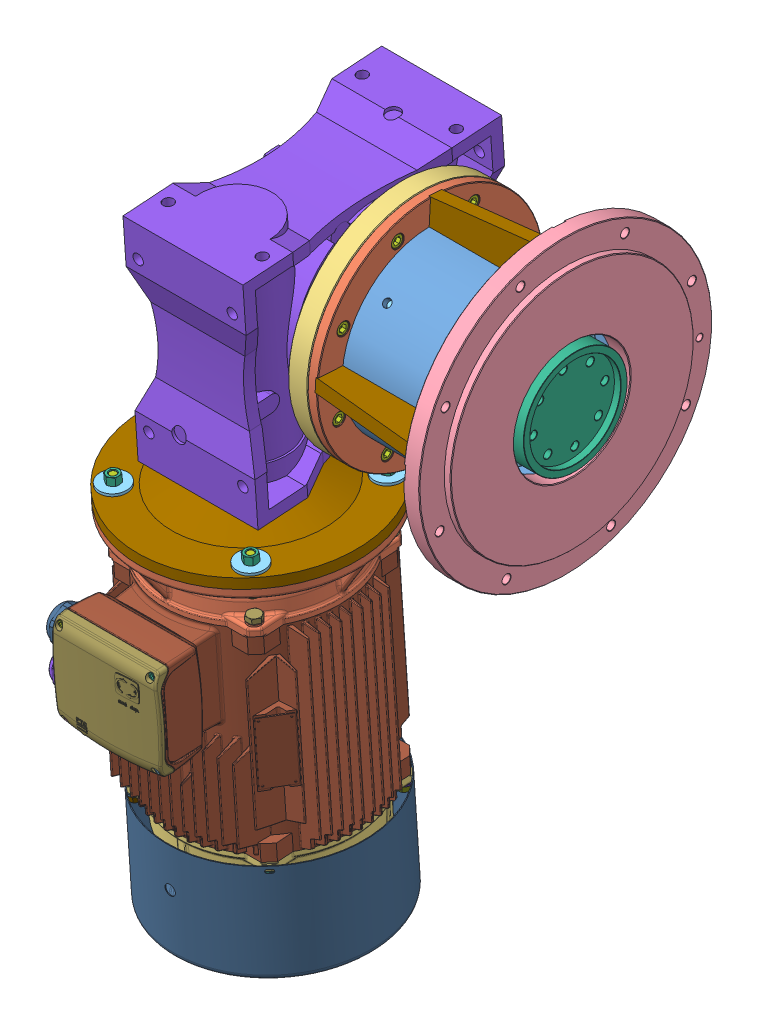
SolidWorks assembly assemblage vireur fini 15.03.2014, configuration Défaut. Lengths in mm.
Overall size (543.11 1035.69 624.79).
75 component instances, 45 part files, 72 mates.
Components (placement in the parent):
- Tube 10 pouce-1: Tube 10 pouce [Défaut] at (-85.911 6.4326 0) size (193.5 273 273)
- Bride tube-1: Bride tube [Défaut] at (-100.411 6.4326 0) x (0 0.056355 0.998411) z (0 -0.998411 0.056355) size (350 19.5 350)
- Bride motoreducteur-1: Bride motoreducteur [Défaut] at (-120.911 6.4326 0) x (0 -0.056355 -0.998411) z (0 0.998411 -0.056355) size (350 30 350)
- bride reducteur GV-1: bride reducteur GV [Défaut] at (107.589 6.4326 0) x (0 -0.998411 0.056355) z (0 -0.056355 -0.998411) size (452 35 452)
- assembla electro du 26;01-1: assembla electro du 26;01 [Défaut] at (-2.5361 8.8665 -55.0034) x (1 0 0) z (0 -0.185944 0.98256) size (265.12 217.99 217.99)
  - Embrayage electro magnetique2-1: Embrayage electro magnetique2 [Défaut] at (-536.0163 -265.8827 54.4967) size (235.12 217.99 217.99)
  - manchon2-1: manchon2 [Défaut] at (135.1251 7.836 54.4967) x (1 0 0) z (0 -0.999668 0.025764) size (110 160 160)
- socket head cap screw_iso-1: socket head cap screw_iso [ISO 4762 M12 x 25 --- 25C] at (-81.911 147.5918 50.7353) x (-1 0 0) z (0 0.471844 0.881682) size (37 18 18)
- socket head cap screw_iso-2: socket head cap screw_iso [ISO 4762 M12 x 25 --- 25C] at (-81.911 -134.7267 -50.7353) x (-1 0 0) z (0 -0.269981 0.962866) size (37 18 18)
- socket head cap screw_iso-3: socket head cap screw_iso [ISO 4762 M12 x 25 --- 25C] at (-81.911 -44.3027 141.1592) x (-1 0 0) z (0 -0.153649 0.988125) size (37 18 18)
- socket head cap screw_iso-4: socket head cap screw_iso [ISO 4762 M12 x 25 --- 25C] at (-81.911 -128.1208 66.2978) x (-1 0 0) z (0 -0.217951 0.97596) size (37 18 18)
- socket head cap screw_iso-5: socket head cap screw_iso [ISO 4762 M12 x 25 --- 25C] at (-81.911 72.7303 134.5534) x (-1 0 0) z (0 0.044455 0.999011) size (37 18 18)
- socket head cap screw_iso-6: socket head cap screw_iso [ISO 4762 M12 x 25 --- 25C] at (-81.911 -59.8652 -134.5534) x (-1 0 0) z (0 -0.742748 0.669571) size (37 18 18)
- socket head cap screw_iso-7: socket head cap screw_iso [ISO 4762 M12 x 25 --- 25C] at (-81.911 57.1678 -141.1592) x (-1 0 0) z (0 0.620775 0.783989) size (37 18 18)
- socket head cap screw_iso-8: socket head cap screw_iso [ISO 4762 M12 x 25 --- 25C] at (-81.911 140.9859 -66.2978) x (-1 0 0) z (0 -0.169231 0.985576) size (37 18 18)
- reducteur box 150-1: reducteur box 150 [Défaut] at (-221.911 6.4326 0) x (0 -0.99765 -0.068517) z (-1 0 0) size (382.6 495 350)
  - box150-1: box150 [Défaut] x (-1 0 0) z (0 0 -1) size (342.6 400 200)
  - Box150 Input Flanges_160B5-1: Box150 Input Flanges_160B5 [Défaut] at (176 150 0) x (-1 0 0) z (0 0 -1) size (40 350 350)
- moteur vireur-1: moteur vireur [Défaut] at (-221.911 -449.9192 119.0118) x (-1 0 0) z (0 0.99765 0.068517) size (357.23 422.95 669.98)
  - COPRIVENTOLA_160-1-1: COPRIVENTOLA_160-1 [Défaut] at origin size (315.45 315.45 164.48)
  - CORPO_STATORE_160L-1-1: CORPO_STATORE_160L-1 [Défaut] at origin size (314.2 318.13 314)
  - DTE12X30-1-1: DTE12X30-1 [Défaut] at origin size (21.94 19 38)
  - DTE12X30_1-1-1: DTE12X30_1-1 [Défaut] at origin size (21.94 19 38)
  - DTE12X30_2-1-1: DTE12X30_2-1 [Défaut] at origin size (21.94 19 38)
  - DTE12X30_3-1-1: DTE12X30_3-1 [Défaut] at origin size (21.94 19 38)
  - DTE12X30_4-1-1: DTE12X30_4-1 [Défaut] at origin size (21.94 19 38)
  - DTE12X30_5-1-1: DTE12X30_5-1 [Défaut] at origin size (21.94 19 38)
  - DTE12X30_6-1-1: DTE12X30_6-1 [Défaut] at origin size (21.94 19 38)
  - DTE12X30_7-1-1: DTE12X30_7-1 [Défaut] at origin size (21.94 19 38)
  - FL_ANTERIORE_160-1-1: FL_ANTERIORE_160-1 [Défaut] at origin size (357.23 357.23 89.01)
  - FL_POSTERIORE_160-1-1: FL_POSTERIORE_160-1 [Défaut] at origin size (337.93 337.93 70.98)
  - GR_RECUPERO160-180-1: GR_RECUPERO160-180 [Défaut] at origin size (198.8 87.06 170.64)
    - DTB6X16-1-1: DTB6X16-1 [Défaut] at origin size (10 22 10)
    - DTB6X16_1-1-1: DTB6X16_1-1 [Défaut] at origin size (10 22 10)
    - DTB6X16_2-1-1: DTB6X16_2-1 [Défaut] at origin size (10 22 10)
    - DTB6X16_3-1-1: DTB6X16_3-1 [Défaut] at origin size (10 22 10)
    - PG_GHISA-1-1: PG_GHISA-1 [Défaut] at origin size (38 50 54)
    - PG_GHISA2-1-1: PG_GHISA2-1 [Défaut] at origin size (23.4 22 25)
    - PG_GHISA_1-1-1: PG_GHISA_1-1 [Défaut] at origin size (38 50 54)
    - RECUPEROBCB160-180-1-1: RECUPEROBCB160-180-1 [Défaut] at origin size (168.93 72.64 158.27)
    - RECUPEROCCB160-180-1-1: RECUPEROCCB160-180-1 [Défaut] at origin size (170.4 32.92 157.34)
  - PAR45-62-12-1-1: PAR45-62-12-1 [Défaut] at origin size (62 62 12)
  - R12--_-_U1751-1-1: R12--_-_U1751-1 [Défaut] at origin size (21 21 2.5)
  - R12--_-_U1751_1-1-1: R12--_-_U1751_1-1 [Défaut] at origin size (21 21 2.5)
  - R12--_-_U1751_2-1-1: R12--_-_U1751_2-1 [Défaut] at origin size (21 21 2.5)
  - R12--_-_U1751_3-1-1: R12--_-_U1751_3-1 [Défaut] at origin size (21 21 2.5)
  - R12--_-_U1751_4-1-1: R12--_-_U1751_4-1 [Défaut] at origin size (21 21 2.5)
  - R12--_-_U1751_5-1-1: R12--_-_U1751_5-1 [Défaut] at origin size (21 21 2.5)
  - R12--_-_U1751_6-1-1: R12--_-_U1751_6-1 [Défaut] at origin size (21 21 2.5)
  - R12--_-_U1751_7-1-1: R12--_-_U1751_7-1 [Défaut] at origin size (21 21 2.5)
  - ROTORE_160-1-1: ROTORE_160-1 [Défaut] at origin size (185 185 622.7)
- socket head cap screw_iso-9: socket head cap screw_iso [ISO 4762 M12 x 45 --- 45C] at (-115.845 -246.5577 239.2942) x (0 0.99765 0.068517) z (-0.068517 -0.068356 0.995305) size (57 18 18)
- socket head cap screw_iso-10: socket head cap screw_iso [ISO 4762 M12 x 45 --- 45C] at (-327.977 -246.5577 239.2942) x (0 0.99765 0.068517) z (-0.068517 -0.068356 0.995305) size (57 18 18)
- socket head cap screw_iso-11: socket head cap screw_iso [ISO 4762 M12 x 45 --- 45C] at (-327.977 -232.0231 27.6607) x (0 0.99765 0.068517) z (-0.068517 -0.068356 0.995305) size (57 18 18)
- socket head cap screw_iso-12: socket head cap screw_iso [ISO 4762 M12 x 45 --- 45C] at (-115.845 -232.0231 27.6607) x (0 0.99765 0.068517) z (-0.068517 -0.068356 0.995305) size (57 18 18)
- plain washer xlarge grade c_iso-1: plain washer xlarge grade c_iso [Washer ISO 7094 - 12] at (-327.977 -204.6564 242.1719) x (0 -0.99765 -0.068517) z (0.068517 -0.068356 0.995305) size (4 44 44)
- plain washer xlarge grade c_iso-2: plain washer xlarge grade c_iso [Washer ISO 7094 - 12] at (-115.845 -190.1218 30.5384) x (0 -0.99765 -0.068517) z (0.068517 -0.068356 0.995305) size (4 44 44)
- plain washer xlarge grade c_iso-3: plain washer xlarge grade c_iso [Washer ISO 7094 - 12] at (-115.845 -204.6564 242.1719) x (0 -0.99765 -0.068517) z (0.068517 -0.068356 0.995305) size (4 44 44)
- plain washer xlarge grade c_iso-4: plain washer xlarge grade c_iso [Washer ISO 7094 - 12] at (-327.977 -190.1218 30.5384) x (0 -0.99765 -0.068517) z (0.068517 -0.068356 0.995305) size (4 44 44)
- hex nut gradec_iso-1: hex nut gradec_iso [Hexagon Nut ISO - 4034 - M12 - C] at (-327.977 -188.4945 243.2819) x (1 0 0) z (0 0.99765 0.068517) size (18 20.78 12.2)
- hex nut gradec_iso-2: hex nut gradec_iso [Hexagon Nut ISO - 4034 - M12 - C] at (-115.845 -173.9598 31.6484) x (1 0 0) z (0 0.99765 0.068517) size (18 20.78 12.2)
- hex nut gradec_iso-3: hex nut gradec_iso [Hexagon Nut ISO - 4034 - M12 - C] at (-115.845 -188.4945 243.2819) x (1 0 0) z (0 0.99765 0.068517) size (18 20.78 12.2)
- hex nut gradec_iso-4: hex nut gradec_iso [Hexagon Nut ISO - 4034 - M12 - C] at (-327.977 -173.9598 31.6484) x (1 0 0) z (0 0.99765 0.068517) size (18 20.78 12.2)
- socket head cap screw_iso-13: socket head cap screw_iso [ISO 4762 M12 x 50 --- 50C] at (-101.911 78.042 -80.1769) x (-1 0 0) z (0 -0.45627 0.889841) size (62 18 18)
- socket head cap screw_iso-14: socket head cap screw_iso [ISO 4762 M12 x 50 --- 50C] at (-101.911 -73.7444 -71.6094) x (-1 0 0) z (0 0.988075 0.153974) size (62 18 18)
- socket head cap screw_iso-15: socket head cap screw_iso [ISO 4762 M12 x 50 --- 50C] at (-101.911 86.6095 71.6094) x (-1 0 0) z (0 0.959903 0.280333) size (62 18 18)
- socket head cap screw_iso-16: socket head cap screw_iso [ISO 4762 M12 x 50 --- 50C] at (-101.911 -65.1769 80.1769) x (-1 0 0) z (0 0.890687 0.454616) size (62 18 18)
- arbre reducteur-1: arbre reducteur [Défaut] at (-327.9431 6.4326 0) x (1 0 0) z (0 -0.99765 -0.068517) size (305.44 72.36 72.36)
- socket head cap screw_iso-17: socket head cap screw_iso [ISO 4762 M12 x 40 --- 40S] at (-0.5005 6.4326 0) x (-1 0 0) z (0 0.860473 -0.509496) size (52 18 18)
- square_iso-1: square_iso [Key ISO 2491 14x6-160-C] at (-320.9431 5.0965 19.4542) x (-1 0 0) z (0 -0.068517 0.99765) size (160 14 6)
- square_iso-3: square_iso [Key ISO 2491 18x7-90-C] at (41.589 2.3381 25.1691) x (-1 0 0) z (0 -0.160568 0.987025) size (90 18 7)
- renfort lanterne-6: renfort lanterne [Défaut] at (105.7082 8.7494 -136.4009) x (-1 0 0) z (0 -0.998411 0.056355) size (189.5 58.72 20)
- renfort lanterne-7: renfort lanterne [Défaut] at (105.589 4.1254 136.573) x (-1 0 0) z (0 0.998411 -0.056355) size (189.5 58.72 20)
- renfort lanterne-8: renfort lanterne [Défaut] at (105.589 -130.0439 -2.3126) x (-1 0 0) z (0 0.056355 0.998411) size (189.5 58.72 20)
- renfort lanterne-9: renfort lanterne [Défaut] at (105.589 142.8735 2.3146) x (-1 0 0) z (0 -0.056355 -0.998411) size (189.5 58.72 20)
Mates (geometry in assembly coordinates):
- Coaxiale1: concentric aligned: cylinder of Tube 10 pouce-1 through (107.589 6.4326 0) axis (1 0 0) radius 135; cylinder of Bride tube-1 through (-85.911 6.4326 0) axis (1 0 0) radius 135
- Coïncidente1: coincident anti-aligned: plane of Tube 10 pouce-1 through (-80.911 141.4326 0) normal (-1 0 0); plane of Bride tube-1 through (-80.911 16.2947 174.7219) normal (1 0 0)
- Coaxiale2: concentric aligned: cylinder of Bride tube-1 through (-85.911 6.4326 0) axis (1 0 0) radius 125; cylinder of Bride motoreducteur-1 through (-100.911 6.4326 0) axis (1 0 0) radius 125
- Coaxiale3: concentric aligned: cylinder of Bride tube-1 through (-100.411 147.5918 50.7353) axis (1 0 0) radius 6.5; cylinder of Bride motoreducteur-1 through (-95.911 147.5918 50.7353) axis (1 0 0) radius 5.1
- Coïncidente3: coincident anti-aligned: plane of Bride tube-1 through (-95.911 13.4769 124.8014) normal (-1 0 0); plane of Bride motoreducteur-1 through (-95.911 -3.4295 -174.7219) normal (1 0 0)
- Coaxiale4: concentric aligned: cylinder of Tube 10 pouce-1 through (107.589 6.4326 0) axis (1 0 0) radius 135; cylinder of bride reducteur GV-1 through (137.589 6.4326 0) axis (1 0 0) radius 135
- Coïncidente4: coincident anti-aligned: plane of Tube 10 pouce-1 through (102.589 142.9326 0) normal (1 0 0); plane of bride reducteur GV-1 through (102.589 -128.3529 7.6079) normal (-1 0 0)
- Coaxiale17: concentric aligned: cylinder of Bride tube-1 through (-93.911 147.5918 50.7353) axis (1 0 0) radius 9.5; cylinder of socket head cap screw_iso-1 through (-50.161 147.5918 50.7353) axis (1 0 0) radius 6
- Coïncidente13: coincident anti-aligned: plane of Bride tube-1 through (-93.911 147.5918 50.7353) normal (1 0 0); plane of socket head cap screw_iso-1 through (-93.911 139.6567 54.9819) normal (-1 0 0)
- Coaxiale18: concentric aligned: cylinder of Bride tube-1 through (-93.911 140.9859 -66.2978) axis (1 0 0) radius 9.5; cylinder of socket head cap screw_iso-8 through (-50.161 140.9859 -66.2978) axis (1 0 0) radius 6
- Coïncidente14: coincident anti-aligned: plane of Bride tube-1 through (-93.911 140.9859 -66.2978) normal (1 0 0); plane of socket head cap screw_iso-8 through (-93.911 132.1157 -67.8208) normal (-1 0 0)
- Coaxiale19: concentric aligned: cylinder of Bride tube-1 through (-93.911 57.1678 -141.1592) axis (1 0 0) radius 9.5; cylinder of socket head cap screw_iso-7 through (-50.161 57.1678 -141.1592) axis (1 0 0) radius 6
- Coïncidente15: coincident anti-aligned: plane of Bride tube-1 through (-93.911 57.1678 -141.1592) normal (1 0 0); plane of socket head cap screw_iso-7 through (-93.911 50.1119 -135.5723) normal (-1 0 0)
- Coaxiale20: concentric aligned: cylinder of Bride tube-1 through (-93.911 -59.8652 -134.5534) axis (1 0 0) radius 9.5; cylinder of socket head cap screw_iso-6 through (-50.161 -59.8652 -134.5534) axis (1 0 0) radius 6
- Coïncidente16: coincident anti-aligned: plane of Bride tube-1 through (-93.911 -59.8652 -134.5534) normal (1 0 0); plane of socket head cap screw_iso-6 through (-93.911 -65.8913 -141.2381) normal (-1 0 0)
- Coaxiale21: concentric aligned: cylinder of Bride tube-1 through (-93.911 -134.7267 -50.7353) axis (1 0 0) radius 9.5; cylinder of socket head cap screw_iso-2 through (-50.161 -134.7267 -50.7353) axis (1 0 0) radius 6
- Coïncidente17: coincident anti-aligned: plane of Bride tube-1 through (-93.911 -134.7267 -50.7353) normal (1 0 0); plane of socket head cap screw_iso-2 through (-93.911 -143.3925 -53.1651) normal (-1 0 0)
- Coaxiale22: concentric aligned: cylinder of Bride tube-1 through (-93.911 72.7303 134.5534) axis (1 0 0) radius 9.5; cylinder of socket head cap screw_iso-5 through (-50.161 72.7303 134.5534) axis (1 0 0) radius 6
- Coïncidente18: coincident anti-aligned: plane of Bride tube-1 through (-93.911 72.7303 134.5534) normal (1 0 0); plane of socket head cap screw_iso-5 through (-93.911 63.7392 134.9535) normal (-1 0 0)
- Coaxiale23: concentric aligned: cylinder of Bride tube-1 through (-93.911 -44.3027 141.1592) axis (1 0 0) radius 9.5; cylinder of socket head cap screw_iso-3 through (-50.161 -44.3027 141.1592) axis (1 0 0) radius 6
- Coïncidente19: coincident anti-aligned: plane of Bride tube-1 through (-93.911 -44.3027 141.1592) normal (1 0 0); plane of socket head cap screw_iso-3 through (-93.911 -53.1959 139.7764) normal (-1 0 0)
- Coaxiale24: concentric aligned: cylinder of Bride tube-1 through (-93.911 -128.1208 66.2978) axis (1 0 0) radius 9.5; cylinder of socket head cap screw_iso-4 through (-50.161 -128.1208 66.2978) axis (1 0 0) radius 6
- Coïncidente20: coincident anti-aligned: plane of Bride tube-1 through (-93.911 -128.1208 66.2978) normal (1 0 0); plane of socket head cap screw_iso-4 through (-93.911 -136.9044 64.3362) normal (-1 0 0)
- Coaxiale34: concentric anti-aligned: cylinder of socket head cap screw_iso-11 through (-327.977 -263.6984 25.4853) axis (0 -0.99765 -0.068517) radius 6; cylinder of plain washer xlarge grade c_iso-4 through (-327.977 -155.2788 32.9314) axis (0 0.99765 0.068517) radius 6.75
- Coïncidente27: coincident anti-aligned: plane of reducteur box 150-1/Box150 Input Flanges_160B5-1 through (-399.011 -185.2547 -40.3286) normal (0 0.99765 0.068517); plane of plain washer xlarge grade c_iso-4 through (-321.2429 -190.0901 30.077) normal (0 -0.99765 -0.068517)
- Coaxiale35: concentric anti-aligned: cylinder of socket head cap screw_iso-10 through (-327.977 -278.2331 237.1188) axis (0 -0.99765 -0.068517) radius 6; cylinder of plain washer xlarge grade c_iso-1 through (-327.977 -169.8135 244.5649) axis (0 0.99765 0.068517) radius 6.75
- Coïncidente28: coincident anti-aligned: plane of reducteur box 150-1/Box150 Input Flanges_160B5-1 through (-399.011 -185.2547 -40.3286) normal (0 0.99765 0.068517); plane of plain washer xlarge grade c_iso-1 through (-321.2429 -204.6247 241.7105) normal (0 -0.99765 -0.068517)
- Coaxiale36: concentric anti-aligned: cylinder of socket head cap screw_iso-9 through (-115.845 -278.2331 237.1188) axis (0 -0.99765 -0.068517) radius 6; cylinder of plain washer xlarge grade c_iso-3 through (-115.845 -169.8135 244.5649) axis (0 0.99765 0.068517) radius 6.75
- Coïncidente29: coincident anti-aligned: plane of reducteur box 150-1/Box150 Input Flanges_160B5-1 through (-399.011 -185.2547 -40.3286) normal (0 0.99765 0.068517); plane of plain washer xlarge grade c_iso-3 through (-109.1108 -204.6247 241.7105) normal (0 -0.99765 -0.068517)
- Coaxiale37: concentric anti-aligned: cylinder of socket head cap screw_iso-12 through (-115.845 -263.6984 25.4853) axis (0 -0.99765 -0.068517) radius 6; cylinder of plain washer xlarge grade c_iso-2 through (-115.845 -155.2788 32.9314) axis (0 0.99765 0.068517) radius 6.75
- Coïncidente30: coincident anti-aligned: plane of reducteur box 150-1/Box150 Input Flanges_160B5-1 through (-399.011 -185.2547 -40.3286) normal (0 0.99765 0.068517); plane of plain washer xlarge grade c_iso-2 through (-109.1108 -190.0901 30.077) normal (0 -0.99765 -0.068517)
- Coaxiale38: concentric anti-aligned: cylinder of socket head cap screw_iso-12 through (-115.845 -263.6984 25.4853) axis (0 -0.99765 -0.068517) radius 6; cylinder of hex nut gradec_iso-2 through (-115.845 -186.1312 30.8125) axis (0 0.99765 0.068517) radius 5.1
- Coïncidente31: coincident anti-aligned: plane of plain washer xlarge grade c_iso-2 through (-93.8967 -186.0279 29.3087) normal (0 0.99765 0.068517); plane of hex nut gradec_iso-2 through (-133.845 -186.1312 30.8125) normal (0 -0.99765 -0.068517)
- Coaxiale39: concentric anti-aligned: cylinder of socket head cap screw_iso-9 through (-115.845 -278.2331 237.1188) axis (0 -0.99765 -0.068517) radius 6; cylinder of hex nut gradec_iso-3 through (-115.845 -200.6658 242.446) axis (0 0.99765 0.068517) radius 5.1
- Coïncidente32: coincident anti-aligned: plane of plain washer xlarge grade c_iso-3 through (-93.8967 -200.5626 240.9422) normal (0 0.99765 0.068517); plane of hex nut gradec_iso-3 through (-133.845 -200.6658 242.446) normal (0 -0.99765 -0.068517)
- Coaxiale40: concentric anti-aligned: cylinder of socket head cap screw_iso-11 through (-327.977 -263.6984 25.4853) axis (0 -0.99765 -0.068517) radius 6; cylinder of hex nut gradec_iso-4 through (-327.977 -186.1312 30.8125) axis (0 0.99765 0.068517) radius 5.1
- Coïncidente33: coincident anti-aligned: plane of plain washer xlarge grade c_iso-4 through (-306.0287 -186.0279 29.3087) normal (0 0.99765 0.068517); plane of hex nut gradec_iso-4 through (-345.977 -186.1312 30.8125) normal (0 -0.99765 -0.068517)
- Coaxiale41: concentric anti-aligned: cylinder of socket head cap screw_iso-10 through (-327.977 -278.2331 237.1188) axis (0 -0.99765 -0.068517) radius 6; cylinder of hex nut gradec_iso-1 through (-327.977 -200.6658 242.446) axis (0 0.99765 0.068517) radius 5.1
- Coïncidente34: coincident anti-aligned: plane of plain washer xlarge grade c_iso-1 through (-306.0287 -200.5626 240.9422) normal (0 0.99765 0.068517); plane of hex nut gradec_iso-1 through (-345.977 -200.6658 242.446) normal (0 -0.99765 -0.068517)
- Coaxiale42: concentric aligned: cylinder of bride reducteur GV-1 through (137.589 6.4326 0) axis (-1 0 0) radius 90; cylinder of assembla electro du 26;01-1/manchon2-1 through (32.589 6.4326 0) axis (-1 0 0) radius 80
- Distance3: distance = 5 mm aligned: plane of assembla electro du 26;01-1/manchon2-1 through (132.589 6.4326 0) normal (1 0 0); plane of bride reducteur GV-1 through (137.589 -180.7695 10.5665) normal (1 0 0)
- Coaxiale47: concentric aligned: cylinder of Bride motoreducteur-1 through (-113.911 -73.7444 -71.6094) axis (1 0 0) radius 9.5; cylinder of socket head cap screw_iso-14 through (-70.161 -73.7444 -71.6094) axis (1 0 0) radius 6
- Coïncidente38: coincident anti-aligned: plane of Bride motoreducteur-1 through (-113.911 -73.7444 -71.6094) normal (1 0 0); plane of socket head cap screw_iso-14 through (-113.911 -75.1301 -62.7167) normal (-1 0 0)
- Coaxiale48: concentric aligned: cylinder of Bride motoreducteur-1 through (-113.911 -65.1769 80.1769) axis (1 0 0) radius 9.5; cylinder of socket head cap screw_iso-16 through (-70.161 -65.1769 80.1769) axis (1 0 0) radius 6
- Coïncidente39: coincident anti-aligned: plane of Bride motoreducteur-1 through (-113.911 -65.1769 80.1769) normal (1 0 0); plane of socket head cap screw_iso-16 through (-113.911 -69.2684 88.1931) normal (-1 0 0)
- Coaxiale49: concentric aligned: cylinder of Bride motoreducteur-1 through (-113.911 86.6095 71.6094) axis (1 0 0) radius 9.5; cylinder of socket head cap screw_iso-15 through (-70.161 86.6095 71.6094) axis (1 0 0) radius 6
- Coïncidente41: coincident anti-aligned: plane of Bride motoreducteur-1 through (-113.911 86.6095 71.6094) normal (1 0 0); plane of socket head cap screw_iso-15 through (-113.911 84.0865 80.2485) normal (-1 0 0)
- Coaxiale50: concentric aligned: cylinder of Bride motoreducteur-1 through (-113.911 78.042 -80.1769) axis (1 0 0) radius 9.5; cylinder of socket head cap screw_iso-13 through (-70.161 78.042 -80.1769) axis (1 0 0) radius 6
- Coïncidente42: coincident anti-aligned: plane of Bride motoreducteur-1 through (-113.911 78.042 -80.1769) normal (1 0 0); plane of socket head cap screw_iso-13 through (-113.911 70.0334 -84.2834) normal (-1 0 0)
- Coïncidente44: coincident anti-aligned: plane of assembla electro du 26;01-1/Embrayage electro magnetique2-1 through (-22.5031 12.8717 1.2186) normal (-1 0 0); plane of arbre reducteur-1 through (-22.5031 4.7196 24.9412) normal (1 0 0)
- Coaxiale54: concentric aligned: cylinder of assembla electro du 26;01-1/Embrayage electro magnetique2-1 through (-122.5287 6.4326 0) axis (1 0 0) radius 25.0639; cylinder of arbre reducteur-1 through (-22.5031 6.4326 0) axis (1 0 0) radius 25
- Coaxiale55: concentric aligned: cylinder of arbre reducteur-1 through (-22.5031 6.4326 0) axis (1 0 0) radius 5.4; cylinder of socket head cap screw_iso-17 through (31.2495 6.4326 0) axis (1 0 0) radius 6
- Coïncidente48: coincident anti-aligned: plane of assembla electro du 26;01-1/Embrayage electro magnetique2-1 through (-12.5005 32.5279 4.9384) normal (1 0 0); plane of socket head cap screw_iso-17 through (-12.5005 11.018 7.7443) normal (-1 0 0)
- Largeur1: width anti-aligned: plane of arbre reducteur-1 through (-337.9431 12.08 19.9338) normal (0 -0.99765 -0.068517); plane of arbre reducteur-1 through (-337.9431 -1.8871 18.9746) normal (0 0.99765 0.068517); plane of square_iso-1 through (-174.9431 11.6689 25.9197) normal (0 0.99765 0.068517); plane of square_iso-1 through (-320.9431 -2.2982 24.9605) normal (0 -0.99765 -0.068517)
- Parallèle1: parallel anti-aligned: plane of arbre reducteur-1 through (-144.9431 5.0965 19.4542) normal (0 -0.068517 0.99765); plane of square_iso-1 through (-320.9431 5.0965 19.4542) normal (0 0.068517 -0.99765)
- Coïncidente49: coincident anti-aligned: plane of arbre reducteur-1 through (-144.9431 5.0965 19.4542) normal (0 -0.068517 0.99765); plane of square_iso-1 through (-320.9431 5.0965 19.4542) normal (0 0.068517 -0.99765)
- Coïncidente50: coincident aligned: plane of arbre reducteur-1 through (-327.9431 6.4326 0) normal (-1 0 0); plane of square_iso-1 through (-327.9431 11.6689 25.9197) normal (-1 0 0)
- Largeur3: width anti-aligned: plane of assembla electro du 26;01-1/manchon2-1 through (-64.2457 11.2213 26.6142) normal (0 -0.987025 -0.160568); plane of assembla electro du 26;01-1/manchon2-1 through (-64.2457 -6.5452 23.724) normal (0 0.987025 0.160568); plane of square_iso-3 through (113.589 10.0973 33.5234) normal (0 0.987025 0.160568); plane of square_iso-3 through (41.589 -7.6691 30.6332) normal (0 -0.987025 -0.160568)
- Coïncidente55: coincident aligned: plane of assembla electro du 26;01-1/manchon2-1 through (32.589 1.2141 32.0783) normal (-1 0 0); plane of square_iso-3 through (32.589 10.0973 33.5234) normal (-1 0 0)
- Coïncidente56: coincident anti-aligned: plane of assembla electro du 26;01-1/manchon2-1 through (97.589 2.3381 25.1691) normal (0 -0.160568 0.987025); plane of square_iso-3 through (41.589 2.3381 25.1691) normal (0 0.160568 -0.987025)
- Largeur11: width anti-aligned: plane of Bride tube-1 through (-83.911 29.8638 237.6722) normal (0 -0.998411 0.056355); plane of Bride tube-1 through (-83.911 9.8956 238.7993) normal (0 0.998411 -0.056355); plane of renfort lanterne-7 through (105.589 24.0937 135.4459) normal (0 0.998411 -0.056355); plane of renfort lanterne-7 through (105.589 4.1254 136.573) normal (0 -0.998411 0.056355)
- Parallèle9: parallel anti-aligned: plane of bride reducteur GV-1 through (105.589 6.4326 0) normal (-1 0 0); plane of renfort lanterne-8 through (105.589 -187.5435 20.9648) normal (1 0 0)
- Largeur16: width anti-aligned: plane of bride reducteur GV-1 through (105.589 284.7344 -5.6927) normal (0 -0.056355 -0.998411); plane of bride reducteur GV-1 through (105.589 283.6073 -25.6609) normal (0 0.056355 0.998411); plane of renfort lanterne-8 through (105.589 -128.9169 17.6557) normal (0 0.056355 0.998411); plane of renfort lanterne-8 through (105.589 -130.0439 -2.3126) normal (0 -0.056355 -0.998411)
- Coïncidente66: coincident anti-aligned: plane of Bride tube-1 through (-83.911 6.4326 0) normal (1 0 0); plane of renfort lanterne-8 through (-83.911 -128.9169 17.6557) normal (-1 0 0)
- Verrouiller8: lock: unknown of Bride tube-1; unknown of renfort lanterne-8
- Verrouiller9: lock: unknown of bride reducteur GV-1; unknown of renfort lanterne-8
- Largeur17: width anti-aligned: plane of Bride tube-1 through (-83.911 240.8092 -23.2452) normal (0 0.056355 0.998411); plane of Bride tube-1 through (-83.911 241.9363 -3.277) normal (0 -0.056355 -0.998411); plane of renfort lanterne-9 through (105.589 141.7464 -17.6536) normal (0 -0.056355 -0.998411); plane of renfort lanterne-9 through (105.589 142.8735 2.3146) normal (0 0.056355 0.998411)
- Parallèle10: parallel anti-aligned: plane of Bride tube-1 through (-83.911 6.4326 0) normal (1 0 0); plane of renfort lanterne-9 through (-83.911 141.7464 -17.6536) normal (-1 0 0)
- Coïncidente68: coincident anti-aligned: plane of Bride tube-1 through (-83.911 6.4326 0) normal (1 0 0); plane of renfort lanterne-9 through (-83.911 141.7464 -17.6536) normal (-1 0 0)
- Verrouiller14: lock: unknown of Bride tube-1; unknown of renfort lanterne-9
- Coïncidente70: coincident anti-aligned: plane of bride reducteur GV-1 through (105.589 6.4326 0) normal (-1 0 0); plane of renfort lanterne-7 through (105.589 27.4028 194.0726) normal (1 0 0)
- Coïncidente71: coincident anti-aligned: plane of bride reducteur GV-1 through (105.589 0.8556 -276.2515) normal (0 -0.998411 0.056355); plane of renfort lanterne-6 through (105.7082 8.7494 -136.4009) normal (0 0.998411 -0.056355)
